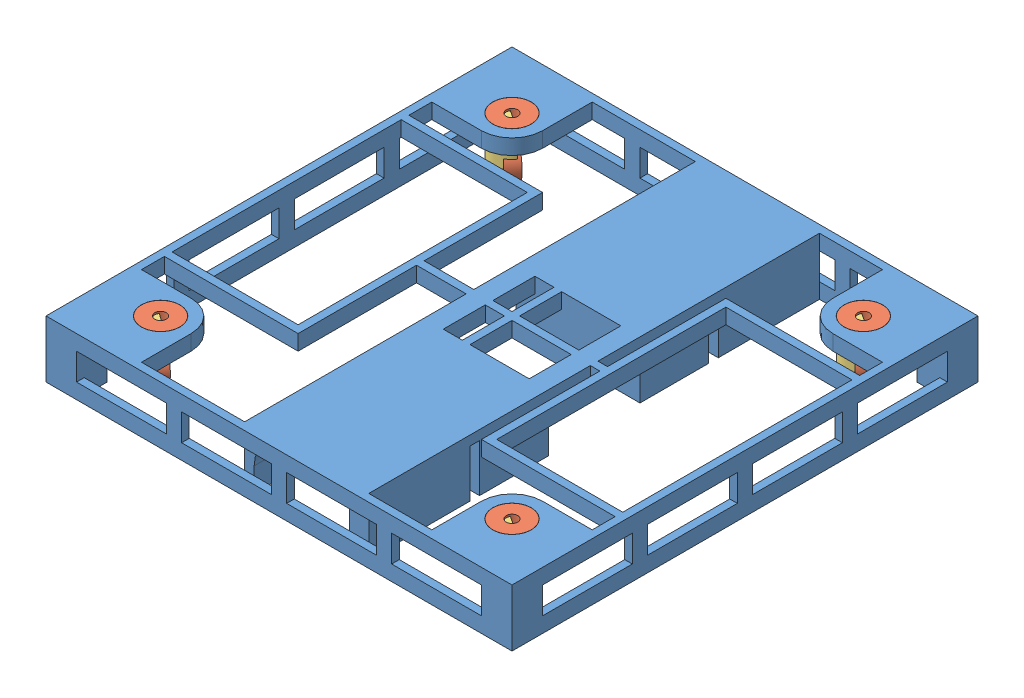
SolidWorks assembly Assem1, configuration Default. Lengths in mm.
Overall size (122 19.02 122).
13 component instances, 3 part files, 24 mates.
Components (placement in the parent):
- Frame-1: Frame [Default] at (-37.4834 43.0829 175.1552) size (122 15 122)
- bearing-1: bearing [Default] at (-22.4834 54.0829 160.1552) size (10 4 10)
- bearing-2: bearing [Default] at (-22.4834 54.0829 68.1552) size (10 4 10)
- bearing-3: bearing [Default] at (69.5166 54.0829 68.1552) size (10 4 10)
- bearing-4: bearing [Default] at (69.5166 54.0829 160.1552) size (10 4 10)
- castor-1: castor [Default] at (-22.4834 54.0829 160.1552) x (-0.811256 0 -0.584691) z (-0.584691 0 0.811256) size (10 14.55 5)
- bearing-5: bearing [Default] at (-26.3789 46.0829 160.4292) x (0.497136 0.79024 0.358297) z (-0.641087 0.612798 -0.462046) size (10 4 10)
- castor-2: castor [Default] at (69.5166 54.0829 68.1552) x (-0.837169 0 -0.546944) z (-0.546944 0 0.837169) size (10 14.55 5)
- castor-3: castor [Default] at (69.5166 54.0829 160.1552) x (-0.837169 0 -0.546944) z (-0.546944 0 0.837169) size (10 14.55 5)
- castor-4: castor [Default] at (-22.4834 54.0829 68.1552) x (-0.837169 0 -0.546944) z (-0.546944 0 0.837169) size (10 14.55 5)
- bearing-6: bearing [Default] at (-26.3622 46.0829 68.6073) x (0.700852 -0.546944 0.457885) z (0.457885 0.837169 0.299148) size (10 4 10)
- bearing-7: bearing [Default] at (65.6378 46.0829 68.6073) x (0.700852 -0.546944 0.457885) z (0.457885 0.837169 0.299148) size (10 4 10)
- bearing-8: bearing [Default] at (65.6378 46.0829 160.6073) x (0.700852 -0.546944 0.457885) z (0.457885 0.837169 0.299148) size (10 4 10)
Mates (geometry in assembly coordinates):
- Concentric1: concentric: cylinder of Frame-1 through (-22.4834 54.0829 160.1552) axis (0 1 0) radius 5.05; cylinder of bearing-1 through (-22.4834 58.0829 160.1552) axis (0 -1 0) radius 5
- Coincident1: coincident: plane of Frame-1 through (-37.4834 58.0829 175.1552) normal (0 1 0); plane of bearing-1 through (-22.4834 58.0829 160.1552) normal (0 1 0)
- Concentric2: concentric: cylinder of Frame-1 through (-22.4834 54.0829 68.1552) axis (0 1 0) radius 5.05; cylinder of bearing-2 through (-22.4834 58.0829 68.1552) axis (0 -1 0) radius 5
- Coincident2: coincident: plane of Frame-1 through (-37.4834 58.0829 175.1552) normal (0 1 0); plane of bearing-2 through (-22.4834 58.0829 68.1552) normal (0 1 0)
- Concentric3: concentric: cylinder of Frame-1 through (69.5166 54.0829 68.1552) axis (0 1 0) radius 5.05; cylinder of bearing-3 through (69.5166 58.0829 68.1552) axis (0 -1 0) radius 5
- Coincident3: coincident: plane of Frame-1 through (-37.4834 58.0829 175.1552) normal (0 1 0); plane of bearing-3 through (69.5166 58.0829 68.1552) normal (0 1 0)
- Concentric4: concentric: cylinder of Frame-1 through (69.5166 54.0829 160.1552) axis (0 1 0) radius 5.05; cylinder of bearing-4 through (69.5166 58.0829 160.1552) axis (0 -1 0) radius 5
- Coincident4: coincident: plane of Frame-1 through (-37.4834 58.0829 175.1552) normal (0 1 0); plane of bearing-4 through (69.5166 58.0829 160.1552) normal (0 1 0)
- Concentric5: concentric: cylinder of bearing-1 through (-22.4834 58.0829 160.1552) axis (0 -1 0) radius 1.5; cylinder of castor-1 through (-22.4834 57.5829 160.1552) axis (0 -1 0) radius 1.5
- Coincident5: coincident: plane of bearing-1 through (-22.4834 54.0829 160.1552) normal (0 -1 0); plane of castor-1 through (-22.4834 54.0829 160.1552) normal (0 1 0)
- Concentric6: concentric: cylinder of castor-1 through (-26.3789 46.0829 160.4292) axis (0.584691 0 -0.811256) radius 1.5; cylinder of bearing-5 through (-24.0401 46.0829 157.1842) axis (-0.584691 0 0.811256) radius 1.5
- Coincident6: coincident: plane of castor-1 through (-23.9451 54.0829 162.1833) normal (0.584691 0 -0.811256); plane of bearing-5 through (-26.3789 46.0829 160.4292) normal (-0.584691 0 0.811256)
- Concentric7: concentric: cylinder of bearing-4 through (69.5166 58.0829 160.1552) axis (0 -1 0) radius 1.5; cylinder of castor-3 through (69.5166 57.5829 160.1552) axis (0 -1 0) radius 1.5
- Coincident7: coincident: plane of bearing-4 through (69.5166 54.0829 160.1552) normal (0 -1 0); plane of castor-3 through (69.5166 54.0829 160.1552) normal (0 1 0)
- Concentric8: concentric: cylinder of bearing-3 through (69.5166 58.0829 68.1552) axis (0 -1 0) radius 1.5; cylinder of castor-2 through (69.5166 57.5829 68.1552) axis (0 -1 0) radius 1.5
- Coincident8: coincident: plane of bearing-3 through (69.5166 54.0829 68.1552) normal (0 -1 0); plane of castor-2 through (69.5166 54.0829 68.1552) normal (0 1 0)
- Concentric9: concentric: cylinder of bearing-2 through (-22.4834 58.0829 68.1552) axis (0 -1 0) radius 1.5; cylinder of castor-4 through (-22.4834 57.5829 68.1552) axis (0 -1 0) radius 1.5
- Coincident9: coincident: plane of bearing-2 through (-22.4834 54.0829 68.1552) normal (0 -1 0); plane of castor-4 through (-22.4834 54.0829 68.1552) normal (0 1 0)
- Concentric10: concentric: cylinder of castor-4 through (-26.3622 46.0829 68.6073) axis (0.546944 0 -0.837169) radius 1.5; cylinder of bearing-6 through (-24.1744 46.0829 65.2586) axis (-0.546944 0 0.837169) radius 1.5
- Coincident10: coincident: plane of castor-4 through (-23.8507 54.0829 70.2481) normal (0.546944 0 -0.837169); plane of bearing-6 through (-26.3622 46.0829 68.6073) normal (-0.546944 0 0.837169)
- Concentric11: concentric: cylinder of castor-2 through (65.6378 46.0829 68.6073) axis (0.546944 0 -0.837169) radius 1.5; cylinder of bearing-7 through (67.8256 46.0829 65.2586) axis (-0.546944 0 0.837169) radius 1.5
- Coincident11: coincident: plane of castor-2 through (68.1493 54.0829 70.2481) normal (0.546944 0 -0.837169); plane of bearing-7 through (65.6378 46.0829 68.6073) normal (-0.546944 0 0.837169)
- Concentric12: concentric: cylinder of castor-3 through (65.6378 46.0829 160.6073) axis (0.546944 0 -0.837169) radius 1.5; cylinder of bearing-8 through (67.8256 46.0829 157.2586) axis (-0.546944 0 0.837169) radius 1.5
- Coincident12: coincident: plane of castor-3 through (68.1493 54.0829 162.2481) normal (0.546944 0 -0.837169); plane of bearing-8 through (65.6378 46.0829 160.6073) normal (-0.546944 0 0.837169)
